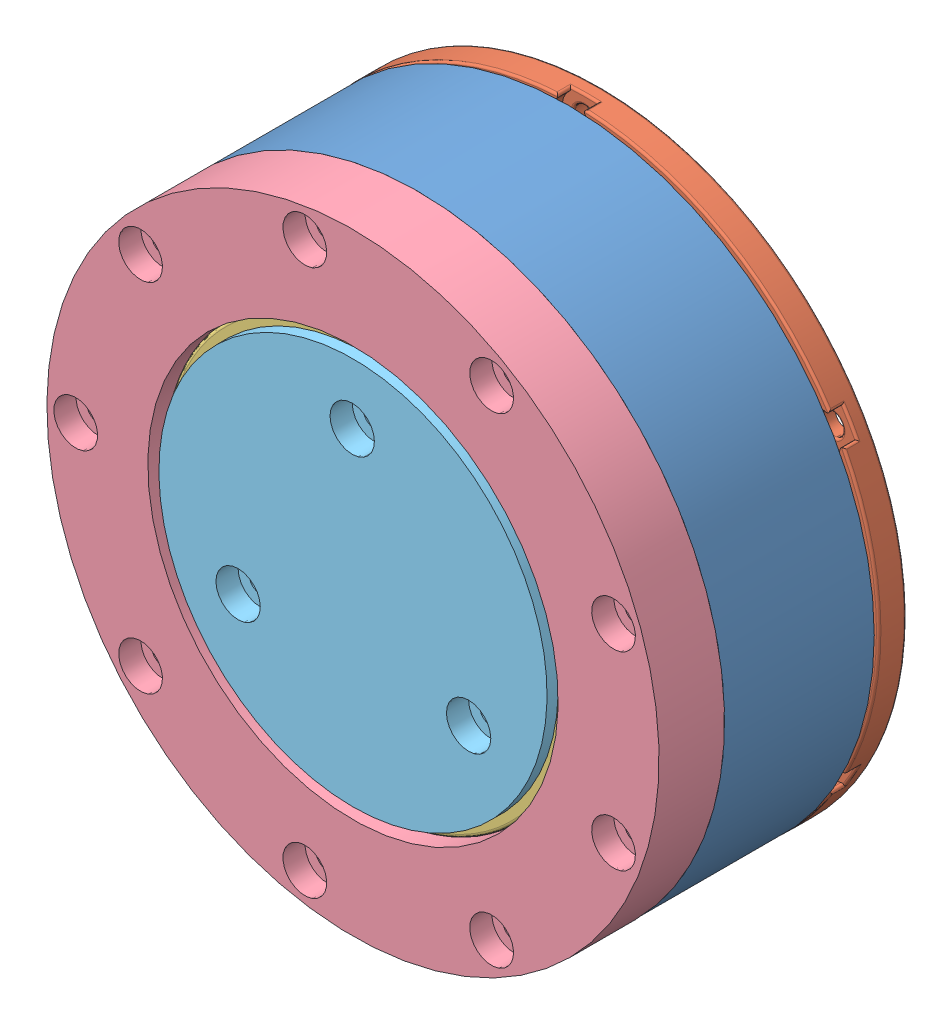
SolidWorks assembly 装配体1, configuration 默认. Lengths in mm.
Overall size (75.52 75.52 25.3).
31 component instances, 18 part files, 65 mates.
Components (placement in the parent):
- 机壳_1-1: 机壳_1 [默认] at (-4.3756 1.5679 48.5) size (55.2 55.2 13.5)
- 零件5-1: 零件5 [默认] at (-4.3756 1.5679 43.1) x (-0.504931 0.86316 0) z (0.86316 0.504931 0) size (55.2 7.4 55.2)
- 30-37-4轴承-1: 30-37-4轴承 [默认] at (-4.3756 1.5679 46) x (0.980761 0.195211 0) z (0 0 1) size (37 37 4)
- 零件7-1: 零件7 [默认] at (-4.3756 1.5679 62.5) x (-0.939693 -0.34202 0) z (0 0 -1) size (55.2 55.2 6)
- 零件9-1: 零件9 [默认] at (-4.3756 1.5679 60.4) x (-0.495053 -0.868863 0) z (0 0 1) size (35 35 5)
- 铜套10-12-6-2: 铜套10-12-6 [默认] at (-4.3756 1.5679 44) x (0.743469 -0.66877 0) z (0 0 1) size (12 12 6)
- 铜套4-8-4-2: 铜套4-8-4 [默认] at (-4.3756 1.5679 60.4) x (0.956656 -0.291222 0) z (0 0 1) size (8 8 4)
- 输入轴1级-1: 输入轴1级 [默认] at (-4.3756 1.5679 43.1) x (-0.993313 0.115456 0) z (0.115456 0.993313 0) size (27 7.4 27)
- 输入轴-1: 输入轴 [默认] at (-4.3756 1.5679 54.5) x (-0.681581 -0.731743 0) z (0 0 -1) size (6 8 12.5)
- 30-37-4轴承-2: 30-37-4轴承 [默认] at (-4.3756 1.5679 60) x (0.833904 -0.55191 0) z (0 0 1) size (37 37 4)
- 摆轮F-1: 摆轮F [默认] at (-3.6439 0.8864 50.5) x (-0.462117 -0.886819 0) z (0 0 1) size (41.45 41.42 4)
- 摆轮F-2: 摆轮F [默认] at (-5.1074 2.2495 54.5) x (0.897755 0.440494 0) z (0 0 1) size (41.45 41.42 4)
- 无刷电机46-1: 无刷电机46 [默认] at (-4.3756 1.5679 22.9) x (0.620739 -0.784018 0) z (-0.784018 -0.620739 0) size (46 26.5 46) (hidden)
- 键-1: 键 [默认] at (-4.3756 1.5679 40.1) x (-0.784018 -0.620739 0) z (-0.620739 0.784018 0) size (18 4.5 18)
- 电机座-1: 电机座 [默认] at (-4.3756 1.5679 43.1) x (-0.36861 -0.929584 0) z (0 0 -1) size (55.2 55.2 31.5) (hidden)
- 同步轮10-1: 同步轮10 [GearTrax] at (-4.3756 1.5679 73.9) x (0.984639 0.174602 0) z (0 0 1) size (38 38 13) (hidden)
- 零件7-2: 零件7 [默认] at (-4.3756 1.5679 83.3) x (0.996679 0.081431 0) z (0 0 1) size (55.2 55.2 6) (hidden)
- 30-37-4轴承-3: 30-37-4轴承 [默认] at (-4.3756 1.5679 81.8) x (0.997668 -0.068248 0) z (0 0 1) size (37 37 4) (hidden)
- 零件9-2: 零件9 [默认] at (-4.3756 1.5679 85.4) x (-0.923728 -0.383049 0) z (0 0 -1) size (35 35 5) (hidden)
- 机壳_1-2: 机壳_1 [默认] at (-4.3756 1.5679 97.3) x (-0.923728 -0.383049 0) z (0 0 -1) size (55.2 55.2 13.5) (hidden)
- 电机座-2: 电机座 [默认] at (-4.3756 1.5679 99.8) x (0.997192 0.074887 0) z (0 0 1) size (55.2 55.2 31.5) (hidden)
- 30-37-4轴承-4: 30-37-4轴承 [默认] at (-4.3756 1.5679 95.8) x (0.901236 0.433329 0) z (0 0 1) size (37 37 4) (hidden)
- 铜套10-12-6-3: 铜套10-12-6 [默认] at (-4.3756 1.5679 93.8) size (12 12 6) (hidden)
- 输入轴1级-2: 输入轴1级 [默认] at (-4.3756 1.5679 100.7) x (-0.278584 0.960412 0) z (-0.960412 -0.278584 0) size (27 7.4 27) (hidden)
- 狗大腿-1: 狗大腿 [默认] at (-4.3756 1.5679 83.3) x (0.938352 0.34568 0) z (0 0 1) size (55.2 177.6 22.9) (hidden)
- 狗大腿盖-1: 狗大腿盖 [默认] at (-4.3756 1.5679 65.4) x (-0.938352 -0.34568 0) z (0 0 -1) size (53.01 138.06 6) (hidden)
- 连接架-1: 连接架 [默认] at (-4.3756 1.5679 43.1) x (0.461348 -0.887219 0) z (0 0 -1) size (51.45 51.45 54.9) (hidden)
- 机壳_1-3: 机壳_1 [默认] at (6.8012 34.4393 24.2996) x (-0.199495 0.141797 -0.969585) z (0.284014 0.955369 0.081282) size (55.2 55.2 13.5) (hidden)
- 零件7-3: 零件7 [默认] at (10.7774 47.8145 25.4376) x (0.912721 -0.243416 -0.328159) z (-0.284014 -0.955369 -0.081282) size (55.2 55.2 6) (hidden)
- 电机座-3: 电机座 [默认] at (11.601 50.5851 25.6733) x (-0.845114 0.209389 0.491873) z (0.284014 0.955369 0.081282) size (55.2 55.2 31.5) (hidden)
- 狗小腿-1: 狗小腿 [GearTrax] at (42.2912 -125.1096 72.9) x (0.65038 -0.759609 0) z (0 0 -1) size (50.75 159.33 20.11) (hidden)
Mates (geometry in assembly coordinates):
- 同心8: concentric: cylinder of 机壳_1-1 through (-4.3756 1.5679 39.7) axis (0 0 1) radius 18.5; cylinder of 30-37-4轴承-1 through (-4.3756 1.5679 50) axis (0 0 -1) radius 18.5
- 重合6: coincident: plane of 机壳_1-1 through (-4.3756 1.5679 50) normal (0 0 -1); plane of 30-37-4轴承-1 through (-4.3756 1.5679 50) normal (0 0 1)
- 重合7: coincident: plane of 零件5-1 through (-4.3756 1.5679 46) normal (0 0 1); plane of 30-37-4轴承-1 through (-4.3756 1.5679 46) normal (0 0 -1)
- 重合8: coincident: plane of 机壳_1-1 through (-4.3756 1.5679 59.5) normal (0 0 1); plane of 零件7-1 through (-4.3756 1.5679 59.5) normal (0 0 -1)
- 同心10: concentric: cylinder of 机壳_1-1 through (-8.7168 26.1881 48.5) axis (0 0 1) radius 1; cylinder of 零件7-1 through (-8.7168 26.1881 62.5) axis (0 0 -1) radius 1
- 重合141: coincident: plane of 零件5-1 through (-4.3756 1.5679 50) normal (0 0 -1); plane of 铜套10-12-6-2 through (-4.3756 1.5679 50) normal (0 0 1)
- 同心151: concentric: cylinder of 零件9-1 through (-4.3756 1.5679 46.2579) axis (0 0 1) radius 4; cylinder of 铜套4-8-4-2 through (-4.3756 1.5679 64.4) axis (0 0 -1) radius 4
- 同心161: concentric: cylinder of 铜套10-12-6-2 through (-4.3756 1.5679 50) axis (0 0 -1) radius 5; cylinder of 输入轴1级-1 through (-4.3756 1.5679 50.5) axis (0 0 -1) radius 5
- 重合161: coincident: plane of 零件5-1 through (-4.3756 1.5679 44) normal (0 0 -1); plane of 输入轴1级-1 through (-4.3756 1.5679 44) normal (0 0 1)
- 同心181: concentric: cylinder of 铜套4-8-4-2 through (-4.3756 1.5679 64.4) axis (0 0 -1) radius 2; cylinder of 输入轴-1 through (-4.3756 1.5679 61.5) axis (0 0 -1) radius 2
- 重合171: coincident: plane of 输入轴1级-1 through (-4.3756 1.5679 50.5) normal (0 0 1); plane of 输入轴-1 through (-3.6439 0.8864 50.5) normal (0 0 -1)
- 同心281: concentric: cylinder of 机壳_1-1 through (-4.3756 1.5679 137.5646) axis (0 0 -1) radius 27.6; cylinder of 零件5-1 through (-4.3756 1.5679 123.6646) axis (0 0 -1) radius 27.6
- 同心311: concentric: cylinder of 零件7-1 through (-4.3756 1.5679 6.6741) axis (0 0 1) radius 18.5; cylinder of 30-37-4轴承-2 through (-4.3756 1.5679 64) axis (0 0 -1) radius 15
- 同心321: concentric: cylinder of 零件9-1 through (-4.3756 1.5679 17.9736) axis (0 0 1) radius 15; cylinder of 30-37-4轴承-2 through (-4.3756 1.5679 64) axis (0 0 -1) radius 15
- 同心331: concentric: cylinder of 机壳_1-1 through (-4.3756 1.5679 137.5646) axis (0 0 -1) radius 27.6; cylinder of 零件7-1 through (-4.3756 1.5679 -18.5646) axis (0 0 1) radius 27.6
- 重合191: coincident: plane of 零件7-1 through (-4.3756 1.5679 60) normal (0 0 1); plane of 30-37-4轴承-2 through (-4.3756 1.5679 60) normal (0 0 -1)
- 重合201: coincident: plane of 零件9-1 through (-4.3756 1.5679 64) normal (0 0 -1); plane of 30-37-4轴承-2 through (-4.3756 1.5679 64) normal (0 0 1)
- 同心341: concentric: cylinder of 输入轴-1 through (-3.6439 0.8864 50.5) axis (0 0 1) radius 3; cylinder of 摆轮F-1 through (-3.6439 0.8864 50.5) axis (0 0 1) radius 6
- 重合221: coincident: plane of 机壳_1-1 through (-4.3756 1.5679 50.5) normal (0 0 1); plane of 摆轮F-1 through (-21.3728 10.2348 50.5) normal (0 0 -1)
- 同心351: concentric: cylinder of 输入轴-1 through (-5.1074 2.2495 58.5) axis (0 0 -1) radius 3; cylinder of 摆轮F-2 through (-5.1074 2.2495 54.5) axis (0 0 1) radius 6
- 重合231: coincident: plane of 摆轮F-1 through (-21.3728 10.2348 54.5) normal (0 0 1); plane of 摆轮F-2 through (3.6336 -15.7866 54.5) normal (0 0 -1)
- 同心352: concentric: cylinder of 零件5-1 through (-4.3756 1.5679 3.1736) axis (0 0 1) radius 6; cylinder of 铜套10-12-6-2 through (-4.3756 1.5679 50) axis (0 0 -1) radius 6
- 重合234: coincident: plane of 无刷电机46-1 through (-18.6526 19.6003 40.1) normal (0 0 1); plane of 键-1 through (-4.3756 1.5679 40.1) normal (0 0 -1)
- 同心356: concentric: cylinder of 无刷电机46-1 through (0.3285 5.2924 40.1) axis (0 0 1) radius 1.25; cylinder of 键-1 through (0.3285 5.2924 43.1) axis (0 0 -1) radius 1.475
- 同心358: concentric: cylinder of 无刷电机46-1 through (-4.3756 1.5679 23.9) axis (0 0 -1) radius 23; cylinder of 电机座-1 through (-4.3756 1.5679 15.1) axis (0 0 1) radius 27.6
- 重合235: coincident: plane of 无刷电机46-1 through (-1.7828 19.9427 15.1) normal (0 0 -1); plane of 电机座-1 through (-4.3756 1.5679 15.1) normal (0 0 1)
- 同心359: concentric: cylinder of 无刷电机46-1 through (-2.0466 -14.2616 22.9) axis (0 0 1) radius 1.25; cylinder of 电机座-1 through (-2.0466 -14.2616 43.1) axis (0 0 -1) radius 1.5
- 同心360: concentric: cylinder of 零件5-1 through (-4.3756 1.5679 123.6646) axis (0 0 -1) radius 27.6; cylinder of 电机座-1 through (-4.3756 1.5679 15.1) axis (0 0 1) radius 27.6
- 重合236: coincident: plane of 零件5-1 through (-4.3756 1.5679 43.1) normal (0 0 -1); plane of 电机座-1 through (-4.3756 1.5679 43.1) normal (0 0 1)
- 同心361: concentric: cylinder of 无刷电机46-1 through (-4.3756 1.5679 23.9) axis (0 0 -1) radius 20.9; cylinder of 键-1 through (-4.3756 1.5679 43.1) axis (0 0 -1) radius 9
- 平行3: parallel: plane of 输入轴1级-1 through (-9.2353 0.8995 46.1) normal (0.115456 0.993313 0); plane of 键-1 through (-4.5142 0.376 45.6) normal (-0.115456 -0.993313 0)
- 同心365: concentric: cylinder of 零件5-1 through (-14.802 7.5086 47) axis (0 0 1) radius 1; cylinder of 零件9-1 through (-14.802 7.5086 63) axis (0 0 -1) radius 1
- 同心366: concentric: cylinder of 零件7-1 through (-4.3756 1.5679 -18.5646) axis (0 0 1) radius 27.6; cylinder of 同步轮10-1 through (-4.3756 1.5679 80.4) axis (0 0 -1) radius 19
- 距离1: distance = 2 mm: plane of 同步轮10-1 through (-4.3756 1.5679 67.4) normal (0 0 -1); plane of 零件7-1 through (-4.3756 1.5679 65.4) normal (0 0 1)
- 同心367: concentric: cylinder of 同步轮10-1 through (-4.3756 1.5679 80.4) axis (0 0 -1) radius 19; cylinder of 零件7-2 through (-4.3756 1.5679 164.3646) axis (0 0 -1) radius 27.6
- 同心368: concentric: cylinder of 零件7-2 through (-4.3756 1.5679 139.1259) axis (0 0 -1) radius 18.5; cylinder of 30-37-4轴承-3 through (-4.3756 1.5679 85.8) axis (0 0 -1) radius 18.5
- 重合239: coincident: plane of 零件7-2 through (-4.3756 1.5679 85.8) normal (0 0 -1); plane of 30-37-4轴承-3 through (-4.3756 1.5679 85.8) normal (0 0 1)
- 同心369: concentric: cylinder of 30-37-4轴承-3 through (-4.3756 1.5679 85.8) axis (0 0 -1) radius 15; cylinder of 零件9-2 through (-4.3756 1.5679 127.8264) axis (0 0 -1) radius 15
- 重合240: coincident: plane of 30-37-4轴承-3 through (-4.3756 1.5679 81.8) normal (0 0 -1); plane of 零件9-2 through (-4.3756 1.5679 81.8) normal (0 0 1)
- 重合241: coincident: plane of 同步轮10-1 through (-4.3756 1.5679 80.4) normal (0 0 1); plane of 零件9-2 through (-4.3756 1.5679 80.4) normal (0 0 -1)
- 同心370: concentric: cylinder of 零件7-2 through (-4.3756 1.5679 164.3646) axis (0 0 -1) radius 27.6; cylinder of 机壳_1-2 through (-4.3756 1.5679 8.2354) axis (0 0 1) radius 27.6
- 重合242: coincident: plane of 零件7-2 through (-4.3756 1.5679 86.3) normal (0 0 1); plane of 机壳_1-2 through (-4.3756 1.5679 86.3) normal (0 0 -1)
- 同心371: concentric: cylinder of 机壳_1-2 through (-4.3756 1.5679 8.2354) axis (0 0 1) radius 27.6; cylinder of 电机座-2 through (-4.3756 1.5679 127.8) axis (0 0 -1) radius 27.6
- 重合243: coincident: plane of 机壳_1-2 through (-4.3756 1.5679 99.8) normal (0 0 1); plane of 电机座-2 through (-4.3756 1.5679 99.8) normal (0 0 -1)
- 同心373: concentric: cylinder of 机壳_1-2 through (-4.3756 1.5679 106.1) axis (0 0 -1) radius 18.5; cylinder of 30-37-4轴承-4 through (-4.3756 1.5679 99.8) axis (0 0 -1) radius 18.5
- 重合245: coincident: plane of 机壳_1-2 through (-4.3756 1.5679 95.8) normal (0 0 1); circle of 30-37-4轴承-4
- 同心374: concentric: cylinder of 30-37-4轴承-4 through (-4.3756 1.5679 99.8) axis (0 0 -1) radius 15; cylinder of 铜套10-12-6-3 through (-4.3756 1.5679 99.8) axis (0 0 -1) radius 6
- 重合246: coincident: plane of 30-37-4轴承-4 through (-4.3756 1.5679 99.8) normal (0 0 1); plane of 铜套10-12-6-3 through (-4.3756 1.5679 99.8) normal (0 0 1)
- 同心375: concentric: cylinder of 铜套10-12-6-3 through (-4.3756 1.5679 99.8) axis (0 0 -1) radius 5; cylinder of 输入轴1级-2 through (-4.3756 1.5679 93.3) axis (0 0 1) radius 5
- 重合247: coincident: plane of 30-37-4轴承-4 through (-4.3756 1.5679 99.8) normal (0 0 1); plane of 输入轴1级-2 through (-4.3756 1.5679 99.8) normal (0 0 -1)
- 同心376: concentric: cylinder of 机壳_1-2 through (-4.3756 1.5679 8.2354) axis (0 0 1) radius 27.6; cylinder of 狗大腿-1 through (-4.3756 1.5679 164.3646) axis (0 0 -1) radius 27.6
- 重合248: coincident: plane of 零件7-2 through (-4.3756 1.5679 80.4) normal (0 0 -1); plane of 狗大腿-1 through (-4.3756 1.5679 80.4) normal (0 0 -1)
- 同心377: concentric: cylinder of 电机座-1 through (-4.3756 1.5679 15.1) axis (0 0 1) radius 27.6; cylinder of 狗大腿盖-1 through (-4.3756 1.5679 59.4) axis (0 0 1) radius 27.6
- 重合249: coincident: plane of 狗大腿-1 through (-4.3756 1.5679 65.4) normal (0 0 -1); plane of 狗大腿盖-1 through (42.2912 -125.1096 65.4) normal (0 0 1)
- 同心378: concentric: cylinder of 狗大腿-1 through (42.2912 -125.1096 94.4) axis (0 0 -1) radius 3.47; cylinder of 狗大腿盖-1 through (42.2912 -125.1096 59.4) axis (0 0 1) radius 3.47
- 同心379: concentric: cylinder of 电机座-1 through (-4.3756 1.5679 15.1) axis (0 0 1) radius 27.6; cylinder of 连接架-1 through (-4.3756 1.5679 11.6) axis (0 0 1) radius 27.6
- 重合250: coincident: plane of 电机座-1 through (-4.3756 1.5679 11.6) normal (0 0 -1); plane of 连接架-1 through (-4.3756 1.5679 11.6) normal (0 0 1)
- 重合251: coincident: plane of 连接架-1 through (5.024 31.3328 43.1) normal (0.301136 0.953581 0); plane of 机壳_1-3
- 同心380: concentric: cylinder of 连接架-1 through (-9.9866 -16.1999 26.1) axis (0.301136 0.953581 0) radius 19; cylinder of 机壳_1-3 through (32.5974 118.647 26.1) axis (-0.301136 -0.953581 0) radius 27.6
- 同心381: concentric: cylinder of 机壳_1-3 through (32.0968 119.5289 31.5389) axis (-0.284014 -0.955369 -0.081282) radius 27.6; cylinder of 零件7-3 through (-12.2461 -29.6321 18.8485) axis (0.284014 0.955369 0.081282) radius 27.6
- 重合252: coincident: plane of 机壳_1-3 through (9.9254 44.9484 25.1937) normal (0.284014 0.955369 0.081282); plane of 零件7-3 through (9.9254 44.9484 25.1937) normal (-0.284014 -0.955369 -0.081282)
- 同心382: concentric: cylinder of 机壳_1-3 through (32.0968 119.5289 31.5389) axis (-0.284014 -0.955369 -0.081282) radius 27.6; cylinder of 电机座-3 through (19.5534 77.3354 27.9492) axis (-0.284014 -0.955369 -0.081282) radius 27.6
- 重合253: coincident: plane of 零件7-3 through (11.601 50.5851 25.6733) normal (0.284014 0.955369 0.081282); plane of 电机座-3 through (11.601 50.5851 25.6733) normal (-0.284014 -0.955369 -0.081282)
- 同心383: concentric: cylinder of 狗大腿-1 through (42.2912 -125.1096 94.4) axis (0 0 -1) radius 3.47; cylinder of 狗小腿-1 through (42.2912 -125.1096 85.9848) axis (0 0 -1) radius 6.5
- 重合255: coincident: plane of 狗大腿盖-1 through (42.2912 -125.1096 63.4) normal (0 0 1); plane of 狗小腿-1 through (42.2912 -125.1096 63.4) normal (0 0 -1)
